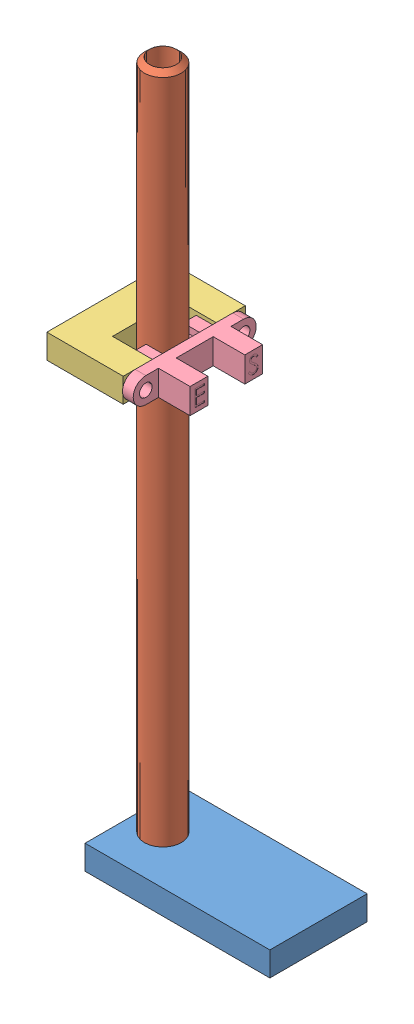
SolidWorks assembly Optical_Encoder_Asm, configuration Default. Lengths in mm.
Overall size (54.99 181.61 32.13).
4 component instances, 4 part files, 11 mates.
Components (placement in the parent):
- Optical_Endcoder_Base-1: Optical_Endcoder_Base [Default] at (-1.8119 -14.3714 8.5628) size (48.26 6.35 25.4)
- Optical_Encoder_Shaft-1: Optical_Encoder_Shaft [Default] at (-18.3219 -14.3714 8.5628) x (0.248316 0 0.968679) z (-0.968679 0 0.248316) size (9.65 181.61 9.65)
- Optical_Encoder_Mount-1: Optical_Encoder_Mount [Default] at (-22.7034 99.446 8.5628) x (0 0 -1) z (1 0 0) size (31.88 6.35 19.94)
- OPB910W_optical_switch-1: OPB910W_optical_switch [Default] at (-12.7339 102.494 8.6263) x (0 0 -1) z (0 -1 0) size (32.13 16.13 6.6)
Mates (geometry in assembly coordinates):
- Concentric1: concentric aligned: circle of Optical_Endcoder_Base-1; circle of Optical_Encoder_Shaft-1
- Coincident2: coincident aligned: plane of Optical_Endcoder_Base-1 through (-1.8119 -14.3714 8.5628) normal (0 -1 0); plane of Optical_Encoder_Shaft-1 through (-18.3219 -14.3714 8.5628) normal (0 -1 0)
- Lock1: lock: unknown of Optical_Endcoder_Base-1; unknown of Optical_Encoder_Shaft-1
- Parallel3: parallel aligned: plane of Optical_Endcoder_Base-1 through (-25.9419 -8.0214 21.2628) normal (-1 0 0); plane of Optical_Encoder_Mount-1 through (-32.6729 105.796 8.5628) normal (-1 0 0)
- Parallel7: parallel anti-aligned: plane of Optical_Endcoder_Base-1 through (-1.8119 -8.0214 8.5628) normal (0 1 0); plane of OPB910W_optical_switch-1 through (-1.6849 99.192 8.6263) normal (0 -1 0)
- Coincident6: coincident anti-aligned: plane of Optical_Encoder_Mount-1 through (-12.7339 105.796 8.5628) normal (1 0 0); plane of OPB910W_optical_switch-1 through (-12.7339 102.494 8.6263) normal (-1 0 0)
- Coincident7: coincident aligned: plane of Optical_Encoder_Mount-1 through (-22.7034 105.796 8.5628) normal (0 1 0); plane of OPB910W_optical_switch-1 through (-1.6849 105.796 8.6263) normal (0 1 0)
- Coincident9: coincident anti-aligned: plane of Optical_Encoder_Mount-1 through (-22.7034 105.796 16.8813) normal (0 0 -1); plane of OPB910W_optical_switch-1 through (-17.8139 104.977 16.8813) normal (0 0 1)
- Distance2: distance = 107.4674 mm anti-aligned: plane of Optical_Encoder_Mount-1 through (-22.7034 99.446 8.5628) normal (0 -1 0); plane of Optical_Endcoder_Base-1 through (-1.8119 -8.0214 8.5628) normal (0 1 0)
- Distance3: distance = 0 mm anti-aligned: plane of Optical_Encoder_Mount-1 through (-23.1479 105.796 8.5628) normal (1 0 0); cylinder of Optical_Encoder_Shaft-1 through (-18.3219 165.9686 8.5628) axis (0 -1 0) radius 4.826
- Distance4: distance = 3.4925 mm anti-aligned: plane of Optical_Encoder_Mount-1 through (-22.7034 105.796 0.2443) normal (0 0 1); cylinder of Optical_Encoder_Shaft-1 through (-18.3219 165.9686 8.5628) axis (0 -1 0) radius 4.826
